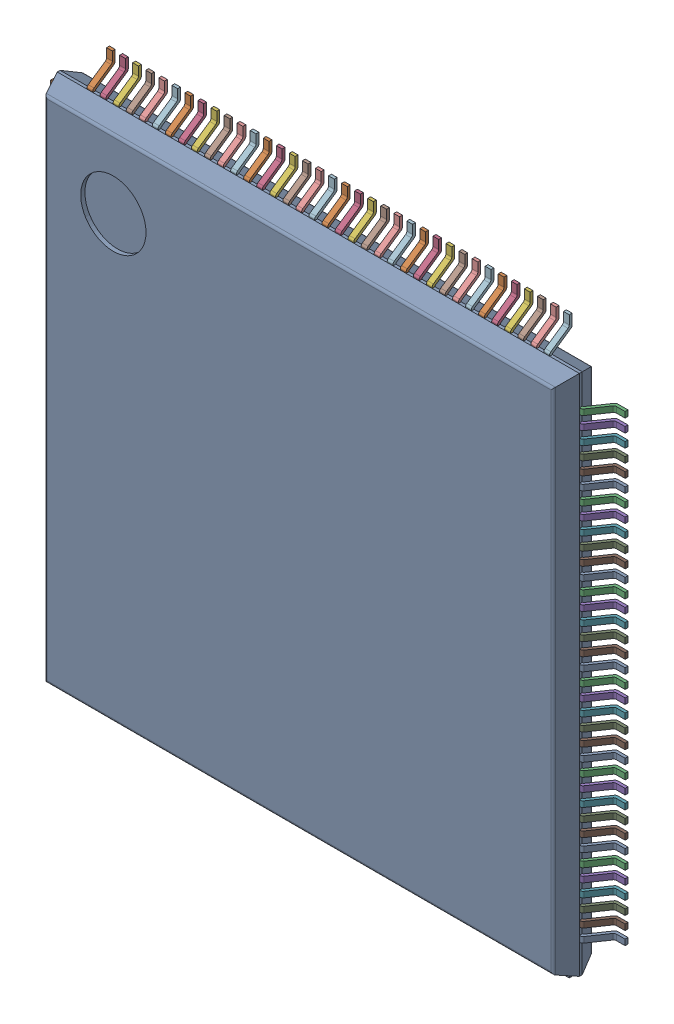
SolidWorks assembly IC1_1.step, configuration Default. Lengths in mm.
Overall size (22 22 1.6).
4 component instances, 3 part files, 0 mates.
Components (placement in the parent):
- 6348794688_1.step-11: 6348794688_1.step [Default] at (417.529 276.576 0) x (1 0 0) z (0 0 1) size (22 22 1.6)
  - Body-1211_1.step-21: Body-1211_1.step [Default] at origin size (20 20 1.5)
  - PinsArrayLR-1212_1.step-21: PinsArrayLR-1212_1.step [Default] at origin size (22 17.72 0.86)
  - PinsArrayTB_1.step-21: PinsArrayTB_1.step [Default] at origin size (17.72 22 0.86)
